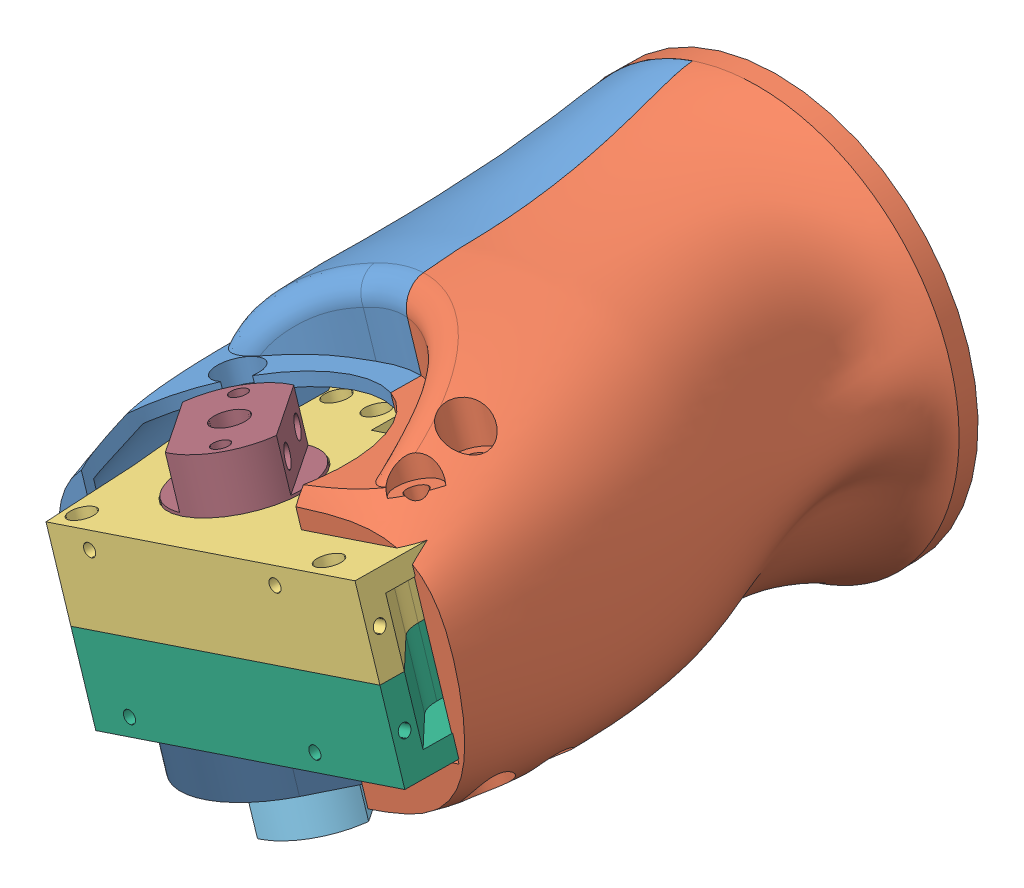
SolidWorks assembly lower arm assm L, configuration Default. Lengths in mm.
Overall size (140.99 140.61 148.59).
31 component instances, 14 part files, 6 mates.
Components (placement in the parent):
- arm lower bottom L-1: arm lower bottom L [Default] at (-74.4796 -36.9206 33.9299) x (-0.948607 -0.316453 0.001636) z (-0.001636 0.010071 0.999948) size (61.83 109.64 120.63)
- arm lower top L-1: arm lower top L [Default] at (-74.4796 -36.9206 33.9299) x (-0.948607 -0.316453 0.001636) z (-0.001636 0.010071 0.999948) size (102.83 109.64 125.02)
- Mirrorgearbox1-1: Mirrorgearbox1 [Default] at (-78.0538 -48.6826 38.5385) x (0.948607 0.316453 -0.001636) z (0.001636 -0.010071 -0.999948) size (90.22 74 134.56)
  - Mirrorservo gearbox-1: Mirrorservo gearbox [Default] at (7.4002 -24.2748 -89.7718) x (1 0 0) z (0 -1 0) size (87.5 78 20)
  - wormscrew-1: wormscrew [Default] at (21.4002 -4.2748 -75.7718) x (-0.47589 -0.879505 0) z (0 0 -1) size (40 40 51)
  - driveshaft cog-1: driveshaft cog [Default] at (-6.5998 -9.2748 -103.2718) x (0.623441 0 -0.78187) z (0 1 0) size (49.29 49.31 47)
  - Mirrorgearbox top-1: Mirrorgearbox top [Default] at (-6.5998 15.7252 -103.2718) x (-1 0 0) z (0 1 0) size (87.5 78 40)
  - HS-805BB-1: HS-805BB [Default] at (2.9002 -19.2748 -28.6693) x (1 0 0) z (0 1 0) size (83 68.8 30)
  - 608ZZ-1: 608ZZ [Default] at (21.4002 -4.2748 -127.5718) x (0.996867 0.079098 0) z (0 0 1) size (22 22 7)
  - 6806 30x42x7-1: 6806 30x42x7 [Default] at (-6.5998 -22.2748 -103.2718) x (0.979879 0 -0.199591) z (0 1 0) size (42 42 7)
  - 6806 30x42x7-2: 6806 30x42x7 [Default] at (-6.5998 9.7252 -103.2718) x (0.968497 0 -0.249026) z (0 -1 0) size (42 42 7)
  - Mirrorbottom plate pot holder-1: Mirrorbottom plate pot holder [Default] at (-6.5998 15.7252 -103.2718) x (0 0 1) z (0 -1 0) size (50 60 10)
  - cog brace-1: cog brace [Default] at (18.6002 9.7252 -104.6718) x (1 0 0) z (0 -1 0) size (8.5 22.65 3)
  - pot cog-1: pot cog [Default] at (18.6002 12.7252 -97.7718) x (0.51355 0 -0.85806) z (0 -1 0) size (28 27.88 7.9)
  - driveshaft-1: driveshaft [Default] at (-6.5998 -9.2748 -103.2718) x (-0.623441 0 0.78187) z (0 -1 0) size (36.44 35.48 27)
  - Pan Head Cross Recess Screw_ISO-1: Pan Head Cross Recess Screw_ISO [ISO 7045 - M3 x 10 - Z --- 10N] at (-26.5998 23.1252 -103.2718) x (0 -1 0) z (0 0 -1) size (12.35 5.6 5.6)
  - Pan Head Cross Recess Screw_ISO-2: Pan Head Cross Recess Screw_ISO [ISO 7045 - M3 x 10 - Z --- 10N] at (-6.5998 23.1252 -123.2718) x (0 -1 0) z (0.495758 0 -0.868461) size (12.35 5.6 5.6)
  - Pan Head Cross Recess Screw_ISO-3: Pan Head Cross Recess Screw_ISO [ISO 7045 - M3 x 10 - Z --- 10N] at (-6.5998 23.1252 -83.2718) x (0 -1 0) z (0.927545 0 -0.373711) size (12.35 5.6 5.6)
  - Pan Head Cross Recess Screw_ISO-4: Pan Head Cross Recess Screw_ISO [ISO 7045 - M5 x 12 - Z --- 12N] at (-34.5998 -13.2748 -42.0718) x (0 0 -1) z (-1 0 0) size (15.63 9.5 9.5)
  - Pan Head Cross Recess Screw_ISO-5: Pan Head Cross Recess Screw_ISO [ISO 7045 - M5 x 12 - Z --- 12N] at (-34.5998 4.7252 -42.0718) x (0 0 -1) z (-1 0 0) size (15.63 9.5 9.5)
  - Pan Head Cross Recess Screw_ISO-6: Pan Head Cross Recess Screw_ISO [ISO 7045 - M3 x 30 - Z --- 25N] at (-27.0895 14.1252 -123.7718) x (0 -1 0) z (0 0 -1) size (32.35 5.6 5.6)
  - Pan Head Cross Recess Screw_ISO-7: Pan Head Cross Recess Screw_ISO [ISO 7045 - M3 x 30 - Z --- 25N] at (-18.0998 -22.6748 -69.7718) x (0 1 0) z (0 0 -1) size (32.35 5.6 5.6)
  - Pan Head Cross Recess Screw_ISO-8: Pan Head Cross Recess Screw_ISO [ISO 7045 - M3 x 30 - Z --- 25N] at (34.9002 14.1252 -82.7718) x (0 -1 0) z (-0.8218 0 -0.569776) size (32.35 5.6 5.6)
  - Pan Head Cross Recess Screw_ISO-9: Pan Head Cross Recess Screw_ISO [ISO 7045 - M3 x 30 - Z --- 25N] at (-5.5998 14.1252 -71.7718) x (0 -1 0) z (0.38373 0 -0.923445) size (32.35 5.6 5.6)
  - Pan Head Cross Recess Screw_ISO-10: Pan Head Cross Recess Screw_ISO [ISO 7045 - M2 x 6 - Z --- 6N] at (18.6002 6.6252 -115.2718) x (0 1 0) z (0.855583 0 0.517665) size (7.57 4 4)
  - Pan Head Cross Recess Screw_ISO-11: Pan Head Cross Recess Screw_ISO [ISO 7045 - M3 x 5 - Z --- 5N] at (-19.8916 -13.6748 -113.8703) x (0 1 0) z (0.934817 0 -0.355129) size (7.35 5.6 5.6)
  - Pan Head Cross Recess Screw_ISO-12: Pan Head Cross Recess Screw_ISO [ISO 7045 - M3 x 5 - Z --- 5N] at (9.2246 -13.6748 -109.4836) x (0 1 0) z (-0.000145 0 -1) size (7.35 5.6 5.6)
  - Pan Head Cross Recess Screw_ISO-13: Pan Head Cross Recess Screw_ISO [ISO 7045 - M3 x 5 - Z --- 5N] at (-9.1325 -13.6748 -86.4615) x (0 1 0) z (-0.12044 0 -0.992721) size (7.35 5.6 5.6)
  - Pan Head Cross Recess Screw_ISO-14: Pan Head Cross Recess Screw_ISO [ISO 7045 - M3 x 30 - Z --- 25N] at (36.9002 14.1252 -123.7718) x (0 -1 0) z (0.993717 0 0.111922) size (32.35 5.6 5.6)
  - Pan Head Cross Recess Screw_ISO-15: Pan Head Cross Recess Screw_ISO [ISO 7045 - M5 x 12 - Z --- 12N] at (40.4002 4.7252 -42.0718) x (0 0 -1) z (0.445798 -0.895134 0) size (15.63 9.5 9.5)
  - Pan Head Cross Recess Screw_ISO-16: Pan Head Cross Recess Screw_ISO [ISO 7045 - M5 x 12 - Z --- 12N] at (40.4002 -13.2748 -42.0718) x (0 0 -1) z (0.583619 -0.812027 0) size (15.63 9.5 9.5)
Mates (geometry in assembly coordinates):
- Coincident1: coincident aligned: plane of ? through (-71.0981 -46.0447 34.0273) normal (0.001636 -0.010071 -0.999948); plane of ? through (-71.0981 -46.0447 34.0273) normal (0.001636 -0.010071 -0.999948)
- Coincident2: coincident: point of ?; point of ?
- Concentric1: concentric anti-aligned: circle of ?; circle of Mirrorgearbox1-1/Mirrorservo gearbox-1
- Parallel1: parallel anti-aligned: plane of ? through (-26.7223 -48.6528 89.129) normal (-0.948607 -0.316453 0.001636); plane of Mirrorgearbox1-1/Mirrorservo gearbox-1 through (-33.1026 -28.6419 89.1846) normal (0.948607 0.316453 -0.001636)
- Coincident4: coincident anti-aligned: plane of ? through (-79.064 -22.8948 88.784) normal (0.316453 -0.948555 0.010071); plane of Mirrorgearbox1-1/Mirrorservo gearbox-1 through (-118.2936 -35.1508 167.1149) normal (-0.316453 0.948555 -0.010071)
- Coincident5: coincident anti-aligned: plane of ? through (-74.4796 -36.9206 33.9299) normal (0.948607 0.316453 -0.001636); plane of ? through (-74.4796 -36.9206 33.9299) normal (-0.948607 -0.316453 0.001636)
